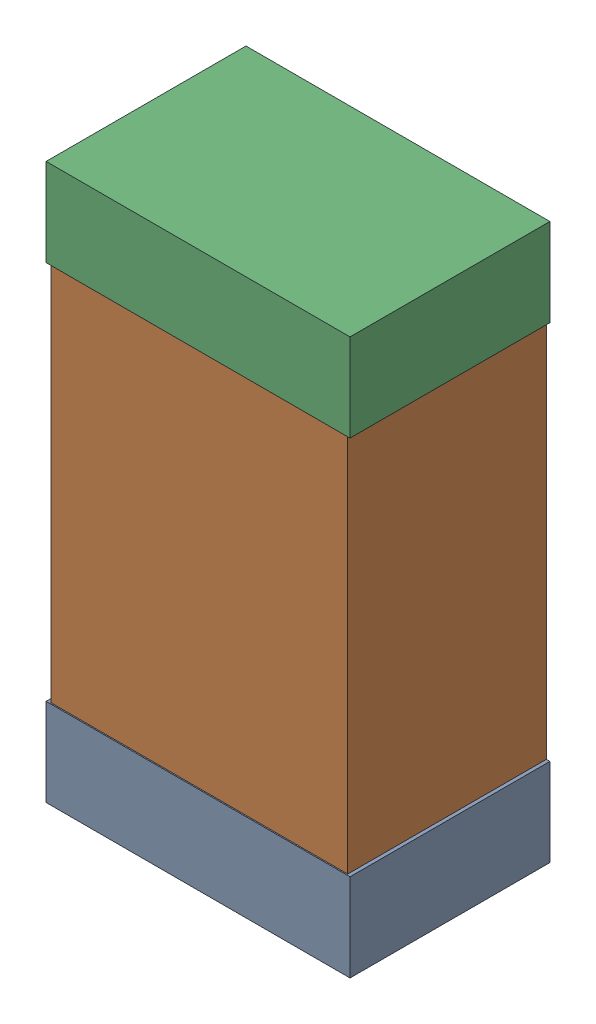
SolidWorks assembly CoutKanaloa_v2.0.0_Power, configuration Default. Lengths in mm.
Overall size (1.3 2.38 0.85).
6 component instances, 2 part files, 0 mates.
Components (placement in the parent):
- 330415056-1: 330415056 [Default] at (51.562 128.032 0) size (1.3 0.38 0.85)
  - Extruded_2-1: Extruded_2 [Default] at origin size (1.3 0.38 0.85)
- 352877008-1: 352877008 [Default] at (51.562 129.032 0) size (1.27 2.2 0.85)
  - Extruded_3-1: Extruded_3 [Default] at origin size (1.27 2.2 0.85)
- 330415056-2: 330415056 [Default] at (51.562 130.032 0) size (1.3 0.38 0.85)
  - Extruded_2-1: Extruded_2 [Default] at origin size (1.3 0.38 0.85)
